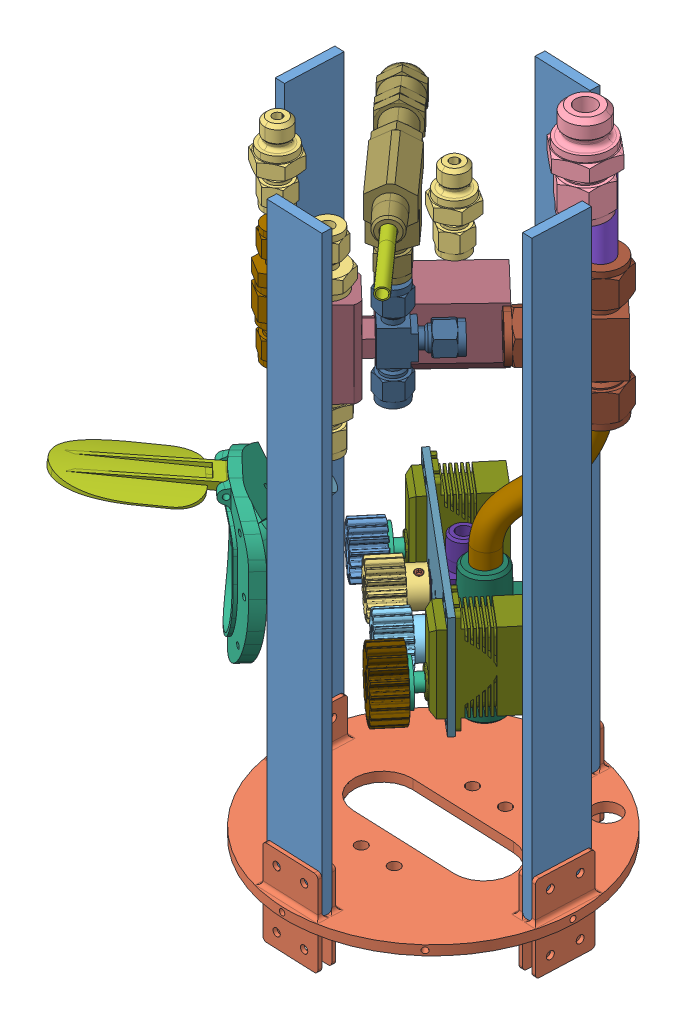
SolidWorks assembly 133000_Valve_Bay_Plumbing, configuration Défaut. Lengths in mm.
Overall size (212.63 353.56 215.74).
47 component instances, 28 part files, 15 mates.
Components (placement in the parent):
- 115200_Valve_Bay-1: 115200_Valve_Bay [Défaut] at (-12.4539 17.9089 -8.6926) x (0.999191 0 0.040223) z (-0.040223 0 0.999191) size (152.4 335 152.4)
  - 115204_Rod-1: 115204_Rod [Valve_Bay] at (209.7958 298.5461 -253.845) x (1 0 0) z (0 -1 0) size (30 5 310)
  - 115101_Thrust_Plate-1: 115101_Thrust_Plate [Défaut] at (209.7958 -16.4539 -313.845) size (152.4 45 152.4)
  - 115204_Rod-2: 115204_Rod [Valve_Bay] at (149.7958 298.5461 -313.845) x (0 0 1) z (0 -1 0) size (30 5 310)
  - 115204_Rod-3: 115204_Rod [Valve_Bay] at (209.7958 298.5461 -373.845) x (-1 0 0) z (0 -1 0) size (30 5 310)
  - 115204_Rod-4: 115204_Rod [Valve_Bay] at (269.7958 298.5461 -313.845) x (0 0 -1) z (0 -1 0) size (30 5 310)
- 133003_raccord_SW_G_4_SS-400-1-4RP-1: 133003_raccord_SW_G_4_SS-400-1-4RP [Défaut] at (173.6527 292.5954 -268.3772) x (0 1 0) z (0 0 1) size (40.39 19.05 22)
- 133003_raccord_SW_G_4_SS-400-1-4RP-2: 133003_raccord_SW_G_4_SS-400-1-4RP [Défaut] at (232.2805 284.5954 -302.3667) x (0 1 0) z (0 0 1) size (40.39 19.05 22)
- 133004_raccord_SW_G_8_SS-400-1-4RP-1: 133004_raccord_SW_G_8_SS-400-1-4RP [Défaut] at (251.105 287.5154 -352.1161) x (0 1 0) z (-0.934249 0 0.356622) size (47.5 26.99 31.16)
- 133008_embout_remplissage-1: 133008_embout_remplissage [Défaut] at (332.9885 29.2294 -446.2871) x (-0.725859 0 -0.687844) z (0.405405 0.807852 -0.42781) size (63.65 135.28 112.81)
  - 236100SA_FILLING_LINE_R01.CATProduct-1: 236100SA_FILLING_LINE_R01.CATProduct [Défaut] at origin size (63.65 135.28 112.81)
    - 236109_SS-TH4TA4TA4-8.CATPart-1: 236109_SS-TH4TA4TA4-8.CATPart [Défaut] at (-1.679 261.5706 -36.5068) x (0 -0.15448 0.987996) z (-0.859917 -0.504306 -0.078852) size (41.66 13.72 13.72) (hidden)
    - 236106_SS-QF4-S-400.CATPart-1: 236106_SS-QF4-S-400.CATPart [Défaut] at (-1.679 259.0593 -20.4459) x (0 0.15448 -0.987996) z (0.999559 0.029342 0.004588) size (44.96 14.3 16.5)
    - 236130_QUICK_FITTING_HOLDER_R05.CATPart-1: 236130_QUICK_FITTING_HOLDER_R05.CATPart [Défaut] at (-1.679 250.22 36.0872) x (-1 0 0) z (0 0.807852 -0.589385) size (63.65 82.68 39.71)
    - 236131_COVER_R01.CATPart-1: 236131_COVER_R01.CATPart [Défaut] at (-1.9173 218.291 -89.0139) x (-1 0 0) z (0 0.470072 0.882628) size (39.54 69.43 6.01)
    - COMPRESSIVE_JOINT.CATPart-1: COMPRESSIVE_JOINT.CATPart [Défaut] at (-1.679 261.806 -38.0125) x (0 -0.15448 0.987996) z (-0.987996 0.152625 0.023864) size (0.5 16 16)
- 133002_check_valve_SS-CHS4-25-1: 133002_check_valve_SS-CHS4-25 [Défaut] at (173.6527 222.9008 -268.3772) x (0 1 0) z (-0.020209 0 0.999796) size (61.72 17.46 20.16)
- 133001_raccord_T_4_SS-400-3-1: 133001_raccord_T_4_SS-400-3 [Défaut] at (201.839 256.9232 -300.7041) x (0 -1 0) z (-0.680479 0 0.732767) size (53.85 14.22 35.14)
- 133007_raccord_T_8_SS_810_3-1: 133007_raccord_T_8_SS_810_3 [Défaut] at (254.1552 193.9312 -357.0404) x (0 1 0) z (0.680479 0 -0.732767) size (72.14 22.35 48.97)
- 133005_pressure_relief_4_SS-4R3A1-2: 133005_pressure_relief_4_SS-4R3A1 [Défaut] at (201.839 299.9006 -300.7041) x (0 -1 0) z (-0.665365 0 -0.746518) size (51.64 20.24 98.81)
- 133006_soleno_quart-1: 133006_soleno_quart [Défaut] at (210.5044 188.9676 -236.7593) x (0.723246 0 0.69059) z (0 1 0) size (28 80.02 47.02)
- 133003_raccord_SW_G_4_SS-400-1-4RP-3: 133003_raccord_SW_G_4_SS-400-1-4RP [Défaut] at (165.7236 160.5196 -302.5493) x (0 1 0) z (0.271213 0 -0.962519) size (40.39 19.05 22)
- 133003_raccord_SW_G_4_SS-400-1-4RP-4: 133003_raccord_SW_G_4_SS-400-1-4RP [Défaut] at (165.7236 262.4156 -302.5493) x (0 -1 0) z (0.697628 0 -0.71646) size (40.39 19.05 22)
- 135000_systeme_servo-1: 135000_systeme_servo [Défaut] at (220.9337 1.9612 -308.7023) x (-0.766044 0 -0.642788) z (0 1 0) size (115.02 63.08 70.73)
  - support vanne servo-1: support vanne servo [Défaut] at (11.6117 -0.2898 118.0217) size (110 3 54)
  - SS-8P6T2-SwagelokCompany-3D-11-16-2022-1: SS-8P6T2-SwagelokCompany-3D-11-16-2022 [Défaut] at (-2.7383 -31.2778 99.9999) x (0 0 1) z (0 1 0) size (67.06 28.45 46.75)
  - Savox_SB2290SG Servo.stp-1: Savox_SB2290SG Servo.stp [Défaut] at (-30.1883 -2.5398 110) x (0 0 1) z (0 1 0) size (54 20.2 42.6)
  - SS-4P4T2-SwagelokCompany-3D-11-16-2022-1: SS-4P4T2-SwagelokCompany-3D-11-16-2022 [Défaut] at (30.8117 -21.3718 99.9999) x (0 0 1) z (0 1 0) size (48.26 18.8 31.12)
  - Savox_SB2290SG Servo.stp-3: Savox_SB2290SG Servo.stp [Défaut] at (55.6117 -2.5398 110.2) x (0 0 1) z (0 1 0) size (54 20.2 42.6)
  - GEAB1.5-20-15-B-10 v1.step-1: GEAB1.5-20-15-B-10 v1.step [Défaut] at (-30.1884 31.7992 99.9999) x (1 0 0) z (0 -1 0) size (33 33 15.01)
    - GEAB1.5-20-15-B-10_b.step-1: GEAB1.5-20-15-B-10_b.step [Défaut] at origin size (33 33 15.01)
  - GEAB1.5-15-15-B-10 v0.step-1: GEAB1.5-15-15-B-10 v0.step [Défaut] at (55.6116 16.3713 100.1999) x (1 0 0) z (0 1 0) size (25.44 25.39 15.01)
    - GEAB1.5-15-15-B-10_b.step-1: GEAB1.5-15-15-B-10_b.step [Défaut] at origin size (25.44 25.39 15.01)
  - GEAB1.5-15-15-B-10.stp-1: GEAB1.5-15-15-B-10.stp [Défaut] at (30.8117 27.2102 99.9999) x (0.94768 0 0.319221) z (0 -1 0) size (25.44 25.39 24.01)
    - SET-SCREW4-4.stp-1: SET-SCREW4-4.stp [Défaut] at (0 5 20) x (0 -1 0) z (-1 0 0) size (4 4 4)
    - GEAB1.5-15-15-B-10_b.stp-1: GEAB1.5-15-15-B-10_b.stp [Défaut] at origin size (25.44 25.39 24.01)
  - GEAB1.5-15-15-B-12.stp-1: GEAB1.5-15-15-B-12.stp [Défaut] at (-2.7383 27.2102 99.9999) x (0.774557 0 -0.632504) z (0 -1 0) size (25.44 25.39 24.01)
    - SET-SCREW4-3.stp-1: SET-SCREW4-3.stp [Défaut] at (0 6 20) x (0 -1 0) z (-1 0 0) size (3 4 4)
    - GEAB1.5-15-15-B-12_b.stp-1: GEAB1.5-15-15-B-12_b.stp [Défaut] at origin size (25.44 25.39 24.01)
  - raccord servo v2.step-1: raccord servo v2.step [Défaut] at (65.6117 16.7992 100.1999) x (1 0 0) z (0 -1 0) size (21 21 7)
  - raccord servo v2.step-2: raccord servo v2.step [Défaut] at (-20.1883 16.7992 99.9999) x (1 0 0) z (0 -1 0) size (21 21 7)
- 133101_tuyau_droit_4-1: 133101_tuyau_droit_4 [50] at (173.6527 266.7771 -268.3772) x (-0.448364 0 0.893851) z (-0.893851 0 -0.448364) size (6.35 30 6.35)
- 133101_tuyau_droit_4-2: 133101_tuyau_droit_4 [50] at (201.839 239.9281 -300.7041) x (0.795427 0 0.60605) z (-0.60605 0 0.795427) size (6.35 30 6.35)
- 133103_tuyau_droit_8-1: 133103_tuyau_droit_8 [Défaut] at (254.1552 254.3505 -357.0404) x (0.959047 0 0.283248) z (-0.283248 0 0.959047) size (12.7 50 12.7)
- 133101_tuyau_droit_4-3: 133101_tuyau_droit_4 [50] at (208.6963 299.9006 -293.0104) x (-0.51985 -0.717687 0.463337) z (-0.535766 0.696366 0.477523) size (6.35 30 6.35)
- 133101_tuyau_droit_4-4: 133101_tuyau_droit_4 [50] at (228.6572 299.9006 -270.6148) x (0.423755 -0.823275 -0.377689) z (-0.61459 -0.567642 0.547778) size (6.35 30 6.35)
- 133102_tuyau_courbe_8-1: 133102_tuyau_courbe_8 [Défaut] at (244.5949 163.3311 -340.4446) x (-0.499166 0 0.866506) z (-0.866506 0 -0.499166) size (56.73 88.44 12.7)
Mates (geometry in assembly coordinates):
- Coaxiale9: concentric anti-aligned: cylinder of 122003_raccord_SW_G_4_SS-400-1-4RP-1 through (173.6527 300.2154 -268.3772) axis (0 1 0) radius 3.175; cylinder of 122002_check_valve_SS-CHS4-25-1 through (173.6527 277.0028 -268.3772) axis (0 -1 0) radius 3.175
- Coaxiale15: concentric anti-aligned: cylinder of 122001_raccord_T_4_SS-400-3-1 through (201.839 249.3032 -300.7041) axis (0 -1 0) radius 3.175; cylinder of 122005_pressure_relief_4_SS-4R3A1-2 through (201.839 266.8806 -300.7041) axis (0 1 0) radius 3.175
- Coaxiale16: concentric anti-aligned: cylinder of 122006_soleno_quart-1 through (165.7236 188.9676 -302.5493) axis (0 -1 0) radius 3.3782; cylinder of 122003_raccord_SW_G_4_SS-400-1-4RP-4 through (165.7236 226.8713 -302.5493) axis (0 1 0) radius 6.5785
- Coaxiale21: concentric aligned: cylinder of 122006_soleno_quart-1 through (165.7236 188.9676 -302.5493) axis (0 -1 0) radius 3.3782; cylinder of 122003_raccord_SW_G_4_SS-400-1-4RP-3 through (165.7236 196.064 -302.5493) axis (0 -1 0) radius 6.5785
- Coïncidente9: coincident anti-aligned: plane of 122006_soleno_quart-1 through (210.5044 188.9676 -236.7593) normal (0 -1 0); plane of 122003_raccord_SW_G_4_SS-400-1-4RP-3 through (165.7236 188.9676 -302.5493) normal (0 1 0)
- Coaxiale22: concentric aligned: cylinder of 122006_soleno_quart-1 through (165.7236 188.9676 -302.5493) axis (0 -1 0) radius 3.3782; cylinder of 122003_raccord_SW_G_4_SS-400-1-4RP-4 through (165.7236 227.9986 -302.5493) axis (0 -1 0) radius 2.413
- Coïncidente10: coincident anti-aligned: plane of 122006_soleno_quart-1 through (210.5044 233.9676 -236.7593) normal (0 1 0); plane of 122003_raccord_SW_G_4_SS-400-1-4RP-4 through (165.7236 233.9676 -302.5493) normal (0 -1 0)
- Coaxiale26: concentric anti-aligned: cylinder of 122001_raccord_T_4_SS-400-3-1 through (214.9749 229.9992 -314.8494) axis (-0.680479 0 0.732767) radius 3.175; cylinder of 122007_raccord_T_8_SS_810_3-1 through (237.3896 229.9992 -338.9864) axis (0.680479 0 -0.732767) radius 6.35
- Coaxiale29: concentric aligned: cylinder of 122002_check_valve_SS-CHS4-25-1 through (173.6527 277.0028 -268.3772) axis (0 -1 0) radius 3.175; cylinder of 122101_tuyau_droit_4-1 through (173.6527 296.7771 -268.3772) axis (0 -1 0) radius 3.175
- Coaxiale30: concentric aligned: cylinder of 122001_raccord_T_4_SS-400-3-1 through (201.839 249.3032 -300.7041) axis (0 -1 0) radius 3.175; cylinder of 122101_tuyau_droit_4-2 through (201.839 269.9281 -300.7041) axis (0 -1 0) radius 2.5
- Coaxiale31: concentric aligned: cylinder of 122007_raccord_T_8_SS_810_3-1 through (254.1552 254.6372 -357.0404) axis (0 -1 0) radius 6.35; cylinder of 122101_tuyau_droit_8-1 through (254.1552 304.3505 -357.0404) axis (0 -1 0) radius 5
- Coaxiale32: concentric anti-aligned: cylinder of 122005_pressure_relief_4_SS-4R3A1-2 through (216.9258 299.9006 -283.7771) axis (0.665365 0 0.746518) radius 3.556; cylinder of 122101_tuyau_droit_4-3 through (228.6572 299.9006 -270.6148) axis (-0.665365 0 -0.746518) radius 3.175
- Coaxiale33: concentric aligned: cylinder of 122101_tuyau_droit_4-3 through (228.6572 299.9006 -270.6148) axis (-0.665365 0 -0.746518) radius 2.5; cylinder of 122101_tuyau_droit_4-4 through (248.6182 299.9006 -248.2193) axis (-0.665365 0 -0.746518) radius 2.5
- Coïncidente12: coincident anti-aligned: plane of 122101_tuyau_droit_4-3 through (228.6572 299.9006 -270.6148) normal (0.665365 0 0.746518); plane of 122101_tuyau_droit_4-4 through (228.6572 299.9006 -270.6148) normal (-0.665365 0 -0.746518)
- Coaxiale35: concentric aligned: cylinder of 122007_raccord_T_8_SS_810_3-1 through (254.1552 205.3612 -357.0404) axis (0 1 0) radius 6.35; cylinder of 122102_tuyau_courbe_8-1 through (254.1552 201.3395 -357.0404) axis (0 1 0) radius 5
